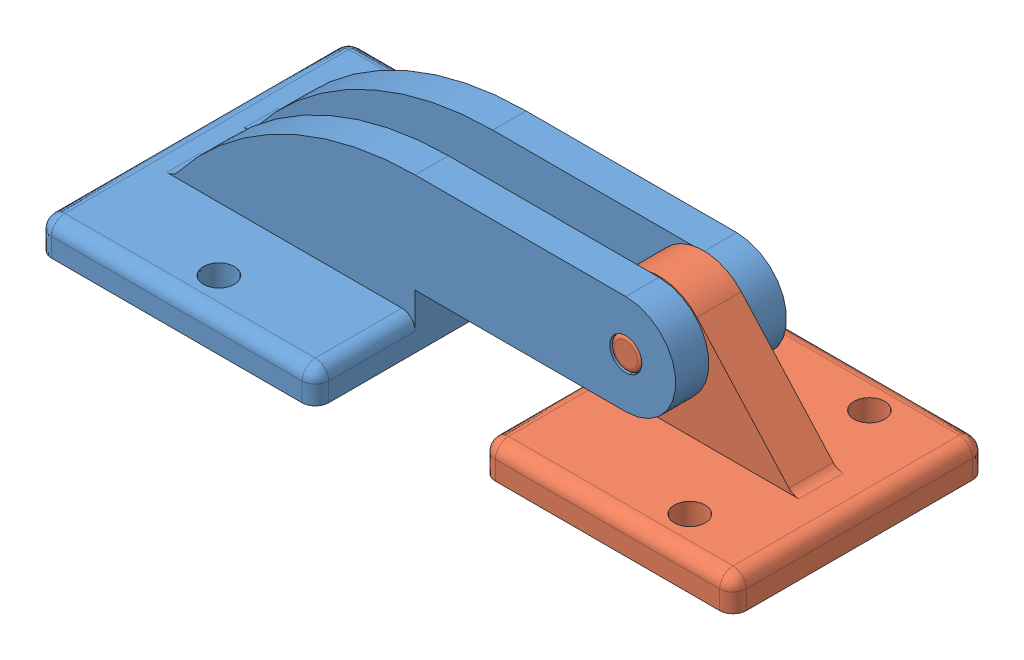
SolidWorks assembly hinge assembly, configuration Default. Lengths in mm.
Overall size (38.14 8.89 17.78).
2 component instances, 2 part files, 3 mates.
Components (placement in the parent):
- hinge big side-1: hinge big side [Default] at origin size (30.8 8.83 17.78)
- hinge small side-1: hinge small side [Default] at (23.0184 0 0) x (-1 0 0) z (0 0 -1) size (14.38 8.89 14.48)
Mates (geometry in assembly coordinates):
- Coincident1: coordinate: point of hinge big side-1
- Coincident3: coincident anti-aligned: plane of hinge small side-1 through (23.0184 0 0) normal (0 0 -1)
- Concentric1: concentric anti-aligned: cylinder of hinge big side-1 through (20.0025 5.969 3.175) axis (0 0 -1) radius 0.9208; cylinder of hinge small side-1 through (20.0025 5.969 -3.175) axis (0 0 1) radius 0.9208
